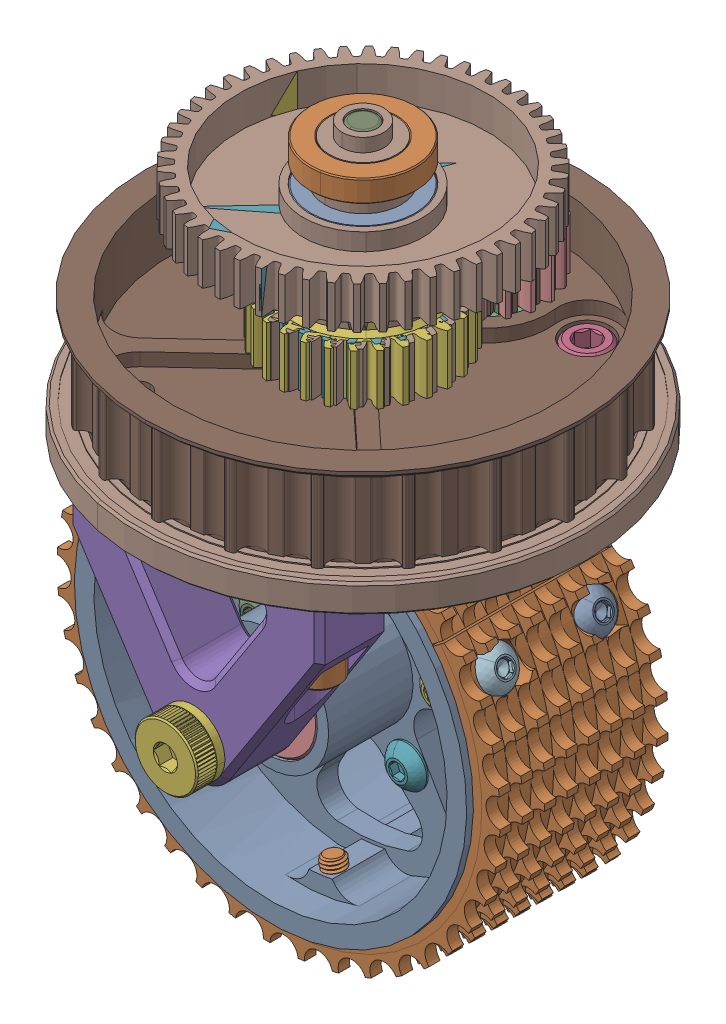
SolidWorks assembly MK4 Turret Assembly_Billet Wheel.STEP, configuration Default. Lengths in mm.
Overall size (140.36 172.84 120.2).
48 component instances, 29 part files, 0 mates.
Components (placement in the parent):
- MK4 Billet Wheel Assembly.STEP-1: MK4 Billet Wheel Assembly.STEP [Default] at (0 50.7435 0.0635) x (0 0 -1) z (-0.607274 0.794493 0) size (42.38 100.13 100.13)
  - Wheel, SDS, Nitrile Tread, 4in X 1.5in, Bearing Bore.STEP-1: Wheel, SDS, Nitrile Tread, 4in X 1.5in, Bearing Bore.STEP [Default] at origin size (42.28 88.9 88.9)
  - Tread, Blue Nitrile 4in X 1.5in.STEP-1: Tread, Blue Nitrile 4in X 1.5in.STEP [Default] at origin size (38.1 100.13 100.13)
  - Bevel Gear, 4515.STEP-1: Bevel Gear, 4515.STEP [Default] at (16.8297 0 0) x (0 -1 0) z (0 0 1) size (68.38 7.77 68.42)
  - Screw, 10-32 X .75, Button, 91255A269_91255A269.STEP-1: Screw, 10-32 X .75, Button, 91255A269_91255A269.STEP [Default] at (-4.826 0 20.6375) x (0 -0.847203 -0.531269) z (-1 0 0) size (9.17 9.17 21.62)
  - Screw, 10-32 X .75, Button, 91255A269_91255A269.STEP-2: Screw, 10-32 X .75, Button, 91255A269_91255A269.STEP [Default] at (-4.826 -17.8726 10.3187) x (0 -0.99925 -0.038711) z (-1 0 0) size (9.17 9.17 21.62)
  - Screw, 10-32 X .75, Button, 91255A269_91255A269.STEP-3: Screw, 10-32 X .75, Button, 91255A269_91255A269.STEP [Default] at (-4.826 -17.8726 -10.3187) x (0 -0.986188 -0.165633) z (-1 0 0) size (9.17 9.17 21.62)
  - Screw, 10-32 X .75, Button, 91255A269_91255A269.STEP-4: Screw, 10-32 X .75, Button, 91255A269_91255A269.STEP [Default] at (-4.826 0 -20.6375) x (0 -0.966455 -0.256836) z (-1 0 0) size (9.17 9.17 21.62)
  - Screw, 10-32 X .75, Button, 91255A269_91255A269.STEP-5: Screw, 10-32 X .75, Button, 91255A269_91255A269.STEP [Default] at (-4.826 17.8726 -10.3187) x (0 -0.95104 -0.309068) z (-1 0 0) size (9.17 9.17 21.62)
  - Screw, 10-32 X .75, Button, 91255A269_91255A269.STEP-6: Screw, 10-32 X .75, Button, 91255A269_91255A269.STEP [Default] at (-4.826 17.8726 10.3187) x (0 -0.947988 -0.318305) z (-1 0 0) size (9.17 9.17 21.62)
  - Screw, 10-32 X .5, Button, 97763A232_97763A232.STEP-1: Screw, 10-32 X .5, Button, 97763A232_97763A232.STEP [Default] at (11.1125 -40.6604 7.1695) x (-0.785325 0.107503 0.609678) z (0 -0.984808 0.173648) size (9.17 9.17 15.27)
  - Screw, 10-32 X .5, Button, 97763A232_97763A232.STEP-2: Screw, 10-32 X .5, Button, 97763A232_97763A232.STEP [Default] at (-11.1125 -40.6604 7.1695) x (-0.636812 0.133886 0.759306) z (0 -0.984808 0.173648) size (9.17 9.17 15.27)
  - Screw, 10-32 X .5, Button, 97763A232_97763A232.STEP-3: Screw, 10-32 X .5, Button, 97763A232_97763A232.STEP [Default] at (-11.1125 -40.6604 -7.1695) x (0.726076 -0.119403 0.677168) z (0 -0.984808 -0.173648) size (9.17 9.17 15.27)
  - Screw, 10-32 X .5, Button, 97763A232_97763A232.STEP-4: Screw, 10-32 X .5, Button, 97763A232_97763A232.STEP [Default] at (11.1125 -40.6604 -7.1695) x (0.841108 -0.09392 0.53265) z (0 -0.984808 -0.173648) size (9.17 9.17 15.27)
  - Screw, 10-32 X .5, Button, 97763A232_97763A232.STEP-5: Screw, 10-32 X .5, Button, 97763A232_97763A232.STEP [Default] at (-11.1125 20.6438 -35.7562) x (0.804058 -0.514897 -0.297276) z (0 0.5 -0.866025) size (9.17 9.17 15.27)
  - Screw, 10-32 X .5, Button, 97763A232_97763A232.STEP-6: Screw, 10-32 X .5, Button, 97763A232_97763A232.STEP [Default] at (11.1125 20.6438 -35.7562) x (0.926716 -0.32542 -0.187881) z (0 0.5 -0.866025) size (9.17 9.17 15.27)
  - Screw, 10-32 X .5, Button, 97763A232_97763A232.STEP-7: Screw, 10-32 X .5, Button, 97763A232_97763A232.STEP [Default] at (11.1125 20.6438 35.7562) x (0.200031 0.848523 -0.489895) z (0 0.5 0.866025) size (9.17 9.17 15.27)
  - Screw, 10-32 X .5, Button, 97763A232_97763A232.STEP-8: Screw, 10-32 X .5, Button, 97763A232_97763A232.STEP [Default] at (-11.1125 20.6438 35.7562) x (0.515054 0.74232 -0.428579) z (0 0.5 0.866025) size (9.17 9.17 15.27)
- Double Gear, 20DP, 28T, 50T.STEP-1: Double Gear, 20DP, 28T, 50T.STEP [Default] at (0 110.1225 0) x (-0.730582 0 -0.682825) z (0 1 0) size (65.97 66.04 34.49)
- Double Gear, 20DP, 25T, 50T.STEP-1: Double Gear, 20DP, 25T, 50T.STEP [Default] at (0 110.1225 0) x (-0.730582 0 -0.682825) z (0 1 0) size (65.97 66.04 34.49)
- Double Gear, 20DP, 27T, 50T.STEP-1: Double Gear, 20DP, 27T, 50T.STEP [Default] at (0 110.1225 0) x (-0.730582 0 -0.682825) z (0 1 0) size (65.97 66.04 34.49)
- Gear, 20DP, 16T, .375Hex, 217-5451.STEP-1: Gear, 20DP, 16T, .375Hex, 217-5451.STEP [Default] at (0 115.2978 -28.0162) x (-0.717682 0 -0.696371) z (0 -1 0) size (22.6 22.6 12.6)
- Gear, 19T, 20DP, .375Hex.STEP-1: Gear, 19T, 20DP, .375Hex.STEP [Default] at (0 115.2978 -28.0162) x (-0.696371 0 0.717682) z (-0.717682 0 -0.696371) size (26.55 12.6 26.64)
- Gear, 17T, 20DP, .375Hex.STEP-1: Gear, 17T, 20DP, .375Hex.STEP [Default] at (0 115.2978 -28.0162) x (0 1 0) z (-0.696371 0 0.717682) size (12.6 23.99 24.09)
- Bevel Gear, 1545.STEP-1: Bevel Gear, 1545.STEP [Default] at (0 84.4935 -28.0162) x (-0.717682 0 -0.696371) z (-0.696371 0 0.717682) size (25.57 14.25 25.63)
- Screw, .25-20 X 1 Socket, 91251A542_91251A542.STEP-1: Screw, .25-20 X 1 Socket, 91251A542_91251A542.STEP [Default] at (-20.32 101.6 30.48) x (0.982082 0 -0.188455) z (0 1 0) size (9.53 9.53 31.75)
- Screw, .25-20 X 1 Socket, 91251A542_91251A542.STEP-2: Screw, .25-20 X 1 Socket, 91251A542_91251A542.STEP [Default] at (20.32 101.6 30.48) x (0.92897 0 -0.370156) z (0 1 0) size (9.53 9.53 31.75)
- Screw, .25-20 X .625, 91251A539_91251A539.STEP-1: Screw, .25-20 X .625, 91251A539_91251A539.STEP [Default] at (-20.32 83.2802 -30.48) x (-0.792805 0 -0.609475) z (0 -1 0) size (9.53 9.53 22.23)
- Screw, .25-20 X .625, 91251A539_91251A539.STEP-2: Screw, .25-20 X .625, 91251A539_91251A539.STEP [Default] at (20.32 83.2802 -30.48) x (-0.899135 0 -0.437672) z (0 -1 0) size (9.53 9.53 22.23)
- Screw, .25-20 X .625, 91251A539_91251A539.STEP-3: Screw, .25-20 X .625, 91251A539_91251A539.STEP [Default] at (0 126.2062 0) x (-0.950706 0 -0.310093) z (0 1 0) size (9.53 9.53 22.23)
- Screw, Shoulder, .375 X 2.5, 5_16-18, 91259A634_91259A634.STEP-1: Screw, Shoulder, .375 X 2.5, 5_16-18, 91259A634_91259A634.STEP [Default] at (0 50.7435 38.4175) x (-0.043278 -0.999063 0) z (-0.999063 0.043278 0) size (14.29 82.55 14.29)
- E Clip, .03125, 97431A310_97431A310.STEP-1: E Clip, .03125, 97431A310_97431A310.STEP [Default] at (0 121.9153 -28.0162) x (0 -1 0) z (0.244803 0 0.969573) size (0.64 12.7 11.34)
- Bearing, A035XPO_SA035XPO.STEP-1: Bearing, A035XPO_SA035XPO.STEP [Default] at (0 95.25 0) x (0.978935 0 0.20417) z (-0.20417 0 0.978935) size (101.6 6.35 101.6)
- Bearing, R8ZZ.STEP-1: Bearing, R8ZZ.STEP [Default] at (0 50.7435 -12.8714) x (0.224275 -0.974526 0) z (0.974526 0.224275 0) size (28.57 7.94 28.57)
- Bearing, R6ZZ.STEP-1: Bearing, R6ZZ.STEP [Default] at (0 50.7435 17.7514) x (0.982629 0.18558 0) z (-0.18558 0.982629 0) size (22.23 7.14 22.23)
- Bearing, 688.STEP-1: Bearing, 688.STEP [Default] at (0 71.4775 -28.0162) x (0 -1 0) z (0 0 1) size (5 16 16)
- Bearing, 6802.STEP-1: Bearing, 6802.STEP [Default] at (0 118.1216 0) x (0.983986 0 -0.178247) z (0.178247 0 0.983986) size (24 5 24)
- Bearing, 6802.STEP-2: Bearing, 6802.STEP [Default] at (0 138.5216 0) x (0.983986 0 -0.178247) z (0.178247 0 0.983986) size (24 5 24)
- Bearing, 6802.STEP-3: Bearing, 6802.STEP [Default] at (0 147.8675 0) x (0.983986 0 -0.178247) z (0.178247 0 0.983986) size (24 5 24)
- Bearing, 6802.STEP-4: Bearing, 6802.STEP [Default] at (0 104.6675 -28.0162) x (0.928172 0 0.372151) z (-0.372151 0 0.928172) size (24 5 24)
- Wheel Mount B Gen2.STEP-1: Wheel Mount B Gen2.STEP [Default] at (0 50.7435 -30.48) x (0 0 1) z (-1 0 0) size (15.88 49.27 57.15)
- Wheel Mount A.STEP-1: Wheel Mount A.STEP [Default] at (0 50.7435 30.48) x (0 0 1) z (-1 0 0) size (17.09 49.74 57.15)
- MK4 Wheel Spacer.STEP-1: MK4 Wheel Spacer.STEP [Default] at (0 50.7435 14.1796) x (0 0 1) z (-1 0 0) size (36.79 15.11 15.11)
- Shim, 8mm ID X 14mm OD X .5mm Thick, 98055A115_98055A115.STEP-1: Shim, 8mm ID X 14mm OD X .5mm Thick, 98055A115_98055A115.STEP [Default] at (0 73.9775 -28.0162) size (14 1 14)
- MK3 Center Column.STEP-1: MK3 Center Column.STEP [Default] at (0 113.0816 0) size (17.27 40.32 17.27)
- magnet.STEP-1: magnet.STEP [Default] at (0 140.7033 0) size (6.35 12.7 6.35)
- MK4 Intermediate Shaft V3.STEP-1: MK4 Intermediate Shaft V3.STEP [Default] at (0 68.3577 -28.0162) x (-0.696371 0 0.717682) z (-0.717682 0 -0.696371) size (16.51 54.51 16.51)
- MK3 Base Pulley V3.STEP-1: MK3 Base Pulley V3.STEP [Default] at (0 98.425 0) size (98.42 27.08 98.42)
